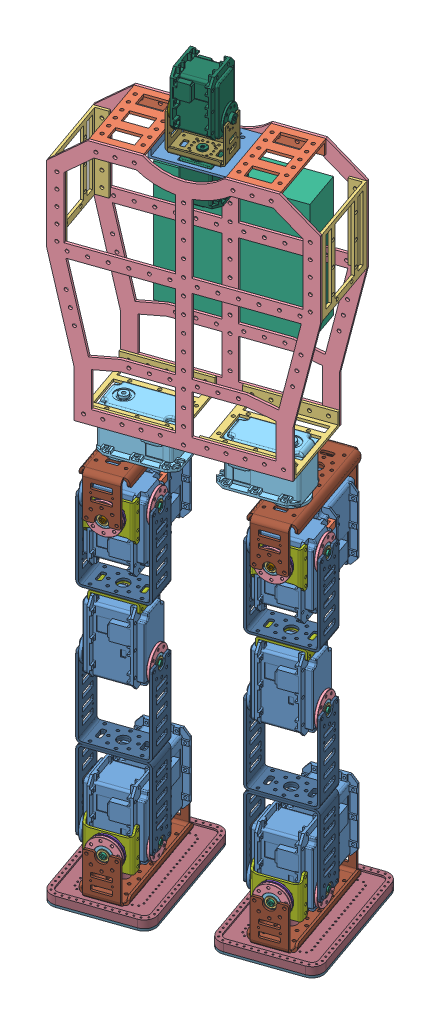
SolidWorks assembly main_new_feet_no_arm_urdf, configuration Default. Lengths in mm.
Overall size (261.31 695.74 185.95).
113 component instances, 25 part files, 43 mates.
Components (placement in the parent):
- leg_l2-1: leg_l2 [Default] at (32.8984 -224.9307 -176.674) x (0.329122 0 0.944287) z (-0.944287 0 0.329122) size (106.88 70.06 58.88)
  - MX-106T_step-1: MX-106T_step [Default] at origin size (40.2 65.92 55.3)
  - MX-106T_step-2: MX-106T_step [Default] at (-44 0 0) x (0 0 1) z (-1 0 0) size (40.2 65.92 55.3)
  - FR08-X101_2017-1: FR08-X101_2017 [Default] at (-27 -7 -17) x (0 -1 0) z (0 0 1) size (28 12.3 4.8)
  - FR08-X101_2017-2: FR08-X101_2017 [Default] at (-27 -7 17) x (0 1 0) z (0 0 -1) size (28 12.3 4.8)
  - RX64-CAP_2017-1: RX64-CAP_2017 [Default] at (0 0 -25.78) x (0.56381 0.825904 0) z (0 0 -1) size (9.5 9.5 2.2)
  - HN05-I101_2017-1: HN05-I101_2017 [Default] at (0 0 -26.02) x (0.824833 -0.565376 0) z (0.565376 0.824833 0) size (28 3.77 28)
  - MF128ZZ_2017-1: MF128ZZ_2017 [Default] at (0 0 -22.3) x (-0.923728 -0.383049 0) z (0.383049 -0.923728 0) size (14 3.48 14)
  - WB_M2.5X8_2017-1: WB_M2.5X8_2017 [Default] at (0 0 -28.08) x (0 0 1) z (0.825904 -0.56381 0) size (5.5 4.5 4.5)
  - FR05-S101_2017-1: FR05-S101_2017 [Default] at (24 0 0) x (0 1 0) z (0 0 1) size (36 9.31 38.02)
  - FR05-F101_2017-1: FR05-F101_2017 [Default] at (24 0 0) x (0 -0.707107 0.707107) z (1 0 0) size (27 27 5)
  - MF128ZZ_2017-2: MF128ZZ_2017 [Default] at (26.3 0 0) x (0 -1 0) z (0 0 1) size (14 3.48 14)
  - WB_M2.5X8_step-1: WB_M2.5X8_step [Default] at (32.08 0 0) x (-1 0 0) z (0 0.546944 0.837169) size (10.5 4.5 4.5)
  - HN05-I101_2017-2: HN05-I101_2017 [Default] at (30.02 0 0) x (0 -1 0) z (0 0 1) size (28 3.77 28)
  - RX64-CAP_2017-2: RX64-CAP_2017 [Default] at (29.78 0 0) x (0 0.837169 -0.546944) z (1 0 0) size (9.5 9.5 2.2)
- leg_l3-2: leg_l3 [Default] at (28.5454 -310.8375 -119.8421) x (0.944287 0 -0.329122) z (0 1 0) size (58.88 41.6 149.21)
  - HW-64106HXL_2017-1: HW-64106HXL_2017 [Default] at (-3.1848 38.233 13.9067) size (56 28 75)
  - FR05-S101_2017-1: FR05-S101_2017 [Default] at (22.8152 52.233 13.9067) x (0 -1 0) z (1 0 0) size (36 9.31 38.02)
  - MX-106T_step-1: MX-106T_step [Default] at (22.8152 52.233 -40.5933) x (0 1 0) z (-1 0 0) size (40.2 65.92 55.3)
  - HN05-I101_2017-1: HN05-I101_2017 [Default] at (48.8352 52.233 -40.5933) x (0 -0.637924 -0.7701) z (0 -0.7701 0.637924) size (28 3.77 28)
  - RX64-CAP_2017-1: RX64-CAP_2017 [Default] at (48.5952 52.233 -40.5933) x (0 0.837169 -0.546944) z (1 0 0) size (9.5 9.5 2.2)
  - MF128ZZ_2017-1: MF128ZZ_2017 [Default] at (45.1152 52.233 -40.5933) x (0 -0.162836 -0.986653) z (0 -0.986653 0.162836) size (14 3.48 14)
  - WB_M2.5X8_2017-1: WB_M2.5X8_2017 [Default] at (50.8952 52.233 -40.5933) x (-1 0 0) z (0 0.546944 0.837169) size (5.5 4.5 4.5)
- leg_l4-1: leg_l4 [Default] at (8.2175 -492.0992 -119.3689) x (0.944287 0 -0.329122) z (0 1 0) size (56 28 150)
  - HW-64106HXL_2017-1: HW-64106HXL_2017 [Default] at (16.1663 31.9894 68.6685) size (56 28 75)
  - HW-64106HXL_2017-2: HW-64106HXL_2017 [Default] at (68.1663 31.9894 68.6685) x (-1 0 0) z (0 0 -1) size (56 28 75)
- leg_l5-1: leg_l5 [Default] at (63.8478 -442.1127 -223.3318) x (0.89528 -0.033567 0.444237) z (-0.424558 -0.366444 0.827931) size (104.02 99.97 119.36)
  - MX-106T_step-1: MX-106T_step [Default] at (-5.1915 -29.4269 71.3073) x (-0.714144 -0.278818 -0.642073) z (-0.699193 0.240141 0.673395) size (40.2 65.92 55.3)
  - MX-106T_step-2: MX-106T_step [Default] at (-36.6138 -41.6949 43.056) x (0.699193 -0.240141 -0.673395) z (-0.714144 -0.278818 -0.642073) size (40.2 65.92 55.3)
  - FR08-X101_2017-1: FR08-X101_2017 [Default] at (-36.5946 -26.3638 62.8539) x (-0.033567 0.929835 -0.366444) z (0.699193 -0.240141 -0.673395) size (28 12.3 4.8)
  - FR08-X101_2017-2: FR08-X101_2017 [Default] at (-12.8221 -34.5286 39.9585) x (0.033567 -0.929835 0.366444) z (-0.699193 0.240141 0.673395) size (28 12.3 4.8)
  - HN05-I101_2017-1: HN05-I101_2017 [Default] at (13.0015 -35.6754 53.7855) x (0.048348 -0.923861 0.379661) z (0.713296 0.298014 0.634347) size (28 3.77 28)
  - RX64-CAP_2017-1: RX64-CAP_2017 [Default] at (12.8337 -35.6178 53.9472) x (-0.430608 0.610431 -0.664793) z (0.699193 -0.240141 -0.673395) size (9.5 9.5 2.2)
  - HN05-I101_2017-2: HN05-I101_2017 [Default] at (16.2471 -21.0568 90.5823) x (0.601193 -0.714144 -0.35856) z (-0.35856 -0.642073 0.677626) size (28 3.77 28)
  - RX64-CAP_2017-2: RX64-CAP_2017 [Default] at (16.0757 -21.1237 90.4282) x (-0.307188 0.949038 -0.070448) z (0.714144 0.278818 0.642073) size (9.5 9.5 2.2)
  - MF128ZZ_2017-1: MF128ZZ_2017 [Default] at (10.4005 -34.7821 56.2906) x (0.048348 -0.923861 0.379661) z (0.713296 0.298014 0.634347) size (14 3.48 14)
  - WB_M2.5X8_2017-1: WB_M2.5X8_2017 [Default] at (14.4419 -36.1701 52.3983) x (-0.699193 0.240141 0.673395) z (0.570706 0.754788 0.323403) size (5.5 4.5 4.5)
  - MF128ZZ_2017-2: MF128ZZ_2017 [Default] at (13.5905 -22.094 88.1938) x (0.601193 -0.714144 -0.35856) z (-0.35856 -0.642073 0.677626) size (14 3.48 14)
  - WB_M2.5X8_2017-2: WB_M2.5X8_2017 [Default] at (17.7183 -20.4824 91.905) x (-0.714144 -0.278818 -0.642073) z (-0.628994 -0.146927 0.763399) size (5.5 4.5 4.5)
  - FR05-S101_2017-1: FR05-S101_2017 [Default] at (11.948 -22.7353 86.717) x (0.033567 -0.929835 0.366444) z (0.699193 -0.240141 -0.673395) size (36 9.31 38.02)
  - FR05-F101_2017-1: FR05-F101_2017 [Default] at (11.948 -22.7353 86.717) x (0.699193 -0.240141 -0.673395) z (0.714144 0.278818 0.642073) size (27 27 5)
- HW-64106HXW_2017-3: HW-64106HXW_2017 [Default] at (141.3019 -187.9307 -286.4689) x (0.329122 0 0.944287) z (0 -1 0) size (105 37.08 40)
- leg_l2-2: leg_l2 [Default] at (148.5736 -224.9307 -216.9914) x (0.329122 0 0.944287) z (-0.944287 0 0.329122) size (106.88 70.06 58.88)
  - MX-106T_step-1: MX-106T_step [Default] at origin size (40.2 65.92 55.3)
  - MX-106T_step-2: MX-106T_step [Default] at (-44 0 0) x (0 0 1) z (-1 0 0) size (40.2 65.92 55.3)
  - FR08-X101_2017-1: FR08-X101_2017 [Default] at (-27 -7 -17) x (0 -1 0) z (0 0 1) size (28 12.3 4.8)
  - FR08-X101_2017-2: FR08-X101_2017 [Default] at (-27 -7 17) x (0 1 0) z (0 0 -1) size (28 12.3 4.8)
  - RX64-CAP_2017-1: RX64-CAP_2017 [Default] at (0 0 -25.78) x (0.56381 0.825904 0) z (0 0 -1) size (9.5 9.5 2.2)
  - HN05-I101_2017-1: HN05-I101_2017 [Default] at (0 0 -26.02) x (0.824833 -0.565376 0) z (0.565376 0.824833 0) size (28 3.77 28)
  - MF128ZZ_2017-1: MF128ZZ_2017 [Default] at (0 0 -22.3) x (-0.923728 -0.383049 0) z (0.383049 -0.923728 0) size (14 3.48 14)
  - WB_M2.5X8_2017-1: WB_M2.5X8_2017 [Default] at (0 0 -28.08) x (0 0 1) z (0.825904 -0.56381 0) size (5.5 4.5 4.5)
  - FR05-S101_2017-1: FR05-S101_2017 [Default] at (24 0 0) x (0 1 0) z (0 0 1) size (36 9.31 38.02)
  - FR05-F101_2017-1: FR05-F101_2017 [Default] at (24 0 0) x (0 -0.707107 0.707107) z (1 0 0) size (27 27 5)
  - MF128ZZ_2017-2: MF128ZZ_2017 [Default] at (26.3 0 0) x (0 -1 0) z (0 0 1) size (14 3.48 14)
  - WB_M2.5X8_step-1: WB_M2.5X8_step [Default] at (32.08 0 0) x (-1 0 0) z (0 0.546944 0.837169) size (10.5 4.5 4.5)
  - HN05-I101_2017-2: HN05-I101_2017 [Default] at (30.02 0 0) x (0 -1 0) z (0 0 1) size (28 3.77 28)
  - RX64-CAP_2017-2: RX64-CAP_2017 [Default] at (29.78 0 0) x (0 0.837169 -0.546944) z (1 0 0) size (9.5 9.5 2.2)
- leg_l3-3: leg_l3 [Default] at (144.2206 -310.8375 -160.1595) x (0.944287 0 -0.329122) z (0 1 0) size (58.88 41.6 149.21)
  - HW-64106HXL_2017-1: HW-64106HXL_2017 [Default] at (-3.1848 38.233 13.9067) size (56 28 75)
  - FR05-S101_2017-1: FR05-S101_2017 [Default] at (22.8152 52.233 13.9067) x (0 -1 0) z (1 0 0) size (36 9.31 38.02)
  - MX-106T_step-1: MX-106T_step [Default] at (22.8152 52.233 -40.5933) x (0 1 0) z (-1 0 0) size (40.2 65.92 55.3)
  - HN05-I101_2017-1: HN05-I101_2017 [Default] at (48.8352 52.233 -40.5933) x (0 -0.637924 -0.7701) z (0 -0.7701 0.637924) size (28 3.77 28)
  - RX64-CAP_2017-1: RX64-CAP_2017 [Default] at (48.5952 52.233 -40.5933) x (0 0.837169 -0.546944) z (1 0 0) size (9.5 9.5 2.2)
  - MF128ZZ_2017-1: MF128ZZ_2017 [Default] at (45.1152 52.233 -40.5933) x (0 -0.162836 -0.986653) z (0 -0.986653 0.162836) size (14 3.48 14)
  - WB_M2.5X8_2017-1: WB_M2.5X8_2017 [Default] at (50.8952 52.233 -40.5933) x (-1 0 0) z (0 0.546944 0.837169) size (5.5 4.5 4.5)
- leg_l4-2: leg_l4 [Default] at (123.8927 -492.0992 -159.6864) x (0.944287 0 -0.329122) z (0 1 0) size (56 28 150)
  - HW-64106HXL_2017-1: HW-64106HXL_2017 [Default] at (16.1663 31.9894 68.6685) size (56 28 75)
  - HW-64106HXL_2017-2: HW-64106HXL_2017 [Default] at (68.1663 31.9894 68.6685) x (-1 0 0) z (0 0 -1) size (56 28 75)
- leg_l5-2: leg_l5 [Default] at (179.523 -442.1127 -263.6493) x (0.89528 -0.033567 0.444237) z (-0.424558 -0.366444 0.827931) size (104.02 99.97 119.36)
  - MX-106T_step-1: MX-106T_step [Default] at (-5.1915 -29.4269 71.3073) x (-0.714144 -0.278818 -0.642073) z (-0.699193 0.240141 0.673395) size (40.2 65.92 55.3)
  - MX-106T_step-2: MX-106T_step [Default] at (-36.6138 -41.6949 43.056) x (0.699193 -0.240141 -0.673395) z (-0.714144 -0.278818 -0.642073) size (40.2 65.92 55.3)
  - FR08-X101_2017-1: FR08-X101_2017 [Default] at (-36.5946 -26.3638 62.8539) x (-0.033567 0.929835 -0.366444) z (0.699193 -0.240141 -0.673395) size (28 12.3 4.8)
  - FR08-X101_2017-2: FR08-X101_2017 [Default] at (-12.8221 -34.5286 39.9585) x (0.033567 -0.929835 0.366444) z (-0.699193 0.240141 0.673395) size (28 12.3 4.8)
  - HN05-I101_2017-1: HN05-I101_2017 [Default] at (13.0015 -35.6754 53.7855) x (0.048348 -0.923861 0.379661) z (0.713296 0.298014 0.634347) size (28 3.77 28)
  - RX64-CAP_2017-1: RX64-CAP_2017 [Default] at (12.8337 -35.6178 53.9472) x (-0.430608 0.610431 -0.664793) z (0.699193 -0.240141 -0.673395) size (9.5 9.5 2.2)
  - HN05-I101_2017-2: HN05-I101_2017 [Default] at (16.2471 -21.0568 90.5823) x (0.601193 -0.714144 -0.35856) z (-0.35856 -0.642073 0.677626) size (28 3.77 28)
  - RX64-CAP_2017-2: RX64-CAP_2017 [Default] at (16.0757 -21.1237 90.4282) x (-0.307188 0.949038 -0.070448) z (0.714144 0.278818 0.642073) size (9.5 9.5 2.2)
  - MF128ZZ_2017-1: MF128ZZ_2017 [Default] at (10.4005 -34.7821 56.2906) x (0.048348 -0.923861 0.379661) z (0.713296 0.298014 0.634347) size (14 3.48 14)
  - WB_M2.5X8_2017-1: WB_M2.5X8_2017 [Default] at (14.4419 -36.1701 52.3983) x (-0.699193 0.240141 0.673395) z (0.570706 0.754788 0.323403) size (5.5 4.5 4.5)
  - MF128ZZ_2017-2: MF128ZZ_2017 [Default] at (13.5905 -22.094 88.1938) x (0.601193 -0.714144 -0.35856) z (-0.35856 -0.642073 0.677626) size (14 3.48 14)
  - WB_M2.5X8_2017-2: WB_M2.5X8_2017 [Default] at (17.7183 -20.4824 91.905) x (-0.714144 -0.278818 -0.642073) z (-0.628994 -0.146927 0.763399) size (5.5 4.5 4.5)
  - FR05-S101_2017-1: FR05-S101_2017 [Default] at (11.948 -22.7353 86.717) x (0.033567 -0.929835 0.366444) z (0.699193 -0.240141 -0.673395) size (36 9.31 38.02)
  - FR05-F101_2017-1: FR05-F101_2017 [Default] at (11.948 -22.7353 86.717) x (0.699193 -0.240141 -0.673395) z (0.714144 0.278818 0.642073) size (27 27 5)
- HW-64106HXW_2017-5: HW-64106HXW_2017 [Default] at (25.6267 -187.9307 -246.1515) x (0.329122 0 0.944287) z (0 -1 0) size (105 37.08 40)
- FR07-H101K-1: FR07-H101K [Default] at (93.0399 76.5333 -190.2227) x (-0.944287 0 0.329122) z (0 1 0) size (44 26 32.5)
- leg_l6_new_feet-1: leg_l6_new_feet [Default] at (87.7926 -593.8701 -169.2992) x (-0.329122 0 -0.944287) z (0 1 0) size (120 80 47.5)
  - HW-64106HXW_2017-1: HW-64106HXW_2017 [Default] at (-3.9692 33.4087 61.4394) size (105 37.08 40)
  - foot_new-1: foot_new [Default] at (44.5308 49.4087 55.9394) x (1 0 0) z (0 -1 0) size (120 7 80)
  - Part4^leg_l6_new_feet-1: Part4^leg_l6_new_feet [Default] at (44.5308 49.4087 55.9394) x (-1 0 0) z (0 0 -1) size (120 80 2) (virtual)
- leg_l6_new_feet-2: leg_l6_new_feet [Default] at (203.4678 -593.8701 -209.6167) x (-0.329122 0 -0.944287) z (0 1 0) size (120 80 47.5)
  - HW-64106HXW_2017-1: HW-64106HXW_2017 [Default] at (-3.9692 33.4087 61.4394) size (105 37.08 40)
  - foot_new-1: foot_new [Default] at (44.5308 49.4087 55.9394) x (1 0 0) z (0 -1 0) size (120 7 80)
  - Part4^leg_l6_new_feet-1: Part4^leg_l6_new_feet [Default] at (44.5308 49.4087 55.9394) x (-1 0 0) z (0 0 -1) size (120 80 2) (virtual)
- head_2_no_camera-1: head_2_no_camera [Default] at (57.4956 210.3096 -243.8587) x (0.944287 0 -0.329122) z (0.329122 0 0.944287) size (44.45 51.16 35.6)
  - MX28_step-1: MX28_step [Default] at (-26.9298 -63.9825 50.4384) x (0 0 1) z (1 0 0) size (35.6 50.71 42.6)
  - MX28_HN07-i101-1: MX28_HN07-i101 [Default] at (-4.5387 -101.2764 62.3462) x (0 0.153917 -0.988084) z (0 0.988084 0.153917) size (22 3.05 22)
  - MF106ZZ-1: MF106ZZ [Défaut] at (-4.3887 -101.2764 62.3462) x (0 0.577041 0.816715) z (0 0.816715 -0.577041) size (11.2 3 11.2)
  - RX28-CAP-1: RX28-CAP [Défaut] at (-4.3887 -101.2764 62.3462) x (0 1 0) z (-1 0 0) size (7.2 7.2 1.8)
- torso_no_arm_motor-1: torso_no_arm_motor [Default] at (90.5715 74.6103 -197.3049) x (0.944287 0 -0.329122) z (0.329122 0 0.944287) size (200 273.5 112.95)
  - torso_frame_head-1: torso_frame_head [Default] at (0 -3.827 -35) size (76 8 58.5)
  - torso_frame_link-1: torso_frame_link [Default] at (-50 -6.241 0) x (0 0 1) z (-1 0 0) size (75.11 12.7 53.47)
  - torso_frame_motor-1: torso_frame_motor [Default] at (-98.857 -88.541 0) x (0 0 1) z (-1 0 0) size (68 70 36.25)
  - torso_main-1: torso_main [Default] at (0 0 34) size (200 228.5 2.29)
  - torso_main-2: torso_main [Default] at (0 0 -36.286) size (200 228.5 2.29)
  - torso_frame_link-2: torso_frame_link [Default] at (50 -6.241 0) x (0 0 1) z (-1 0 0) size (75.11 12.7 53.47)
  - torso_frame_motor-2: torso_frame_motor [Default] at (98.857 -88.541 0) x (0 0 -1) z (1 0 0) size (68 70 36.25)
  - torso_frame_motor-3: torso_frame_motor [Default] at (10 -220.898 0) x (0 0 -1) z (0 -1 0) size (68 70 36.25)
  - torso_frame_motor-4: torso_frame_motor [Default] at (-10 -220.898 0) x (0 0 1) z (0 -1 0) size (68 70 36.25)
  - MX-64T_step-3: MX-64T_step [Default] at (61.25 -239.041 0) x (0 0 -1) z (0 -1 0) size (40.2 62.1 50)
  - MX-64T_step-4: MX-64T_step [Default] at (-61.25 -239.041 0) x (0 0 1) z (0 -1 0) size (40.2 62.1 50)
  - MX28_step-1: MX28_step [Default] at (11.9078 -61.4181 -29.7938) x (-1 0 0) z (0 1 0) size (35.6 50.71 42.6)
  - nuc-1: nuc [Default] at (0 -108.0269 -54.066) size (114.3 111.76 35.56)
- Part1^main_new_feet_no_arm_urdf-1: Part1^main_new_feet_no_arm_urdf [Default] at origin (virtual)
Mates (geometry in assembly coordinates):
- Concentric3: concentric anti-aligned: cylinder of leg_l2-1/HN05-I101_2017-1 through (57.4688 -224.9307 -185.2377) axis (-0.944287 0 0.329122) radius 14; cylinder of leg_l3-2/HW-64106HXL_2017-1 through (59.3385 -224.9307 -185.8894) axis (0.944287 0 -0.329122) radius 5.1
- Concentric4: concentric anti-aligned: cylinder of leg_l3-2/HN05-I101_2017-1 through (57.4688 -351.4307 -185.2377) axis (-0.944287 0 0.329122) radius 14; cylinder of leg_l4-1/HW-64106HXL_2017-1 through (59.3385 -351.4307 -185.8894) axis (0.944287 0 -0.329122) radius 5.1
- Concentric5: concentric anti-aligned: cylinder of leg_l4-1/HW-64106HXL_2017-2 through (6.4584 -495.4307 -167.4586) axis (-0.944287 0 0.329122) radius 5.1; cylinder of leg_l5-1/MX-106T_step-1 through (3.4461 -495.4307 -166.4087) axis (0.944287 0 -0.329122) radius 5
- Coincident5: coincident anti-aligned: plane of leg_l4-1/HW-64106HXL_2017-2 through (8.347 -495.4307 -168.1168) normal (0.944287 0 -0.329122); plane of leg_l5-1/MX-106T_step-1 through (8.347 -495.4307 -168.1168) normal (-0.944287 0 0.329122)
- Coincident6: coincident anti-aligned: plane of leg_l2-1/MX-106T_step-1 through (8.347 -224.9307 -168.1168) normal (-0.944287 0 0.329122); plane of leg_l3-2/HW-64106HXL_2017-1 through (8.347 -224.9307 -168.1168) normal (0.944287 0 -0.329122)
- Coincident7: coincident anti-aligned: plane of leg_l2-1/MX-106T_step-1 through (8.347 -224.9307 -168.1168) normal (-0.944287 0 0.329122); plane of leg_l3-2/HW-64106HXL_2017-1 through (8.347 -224.9307 -168.1168) normal (0.944287 0 -0.329122)
- Coincident8: coincident anti-aligned: plane of leg_l3-2/MX-106T_step-1 through (8.347 -351.4307 -168.1168) normal (-0.944287 0 0.329122); plane of leg_l4-1/HW-64106HXL_2017-1 through (8.347 -351.4307 -168.1168) normal (0.944287 0 -0.329122)
- Concentric8: concentric aligned: cylinder of HW-64106HXW_2017-3 through (159.4347 -224.9307 -185.83) axis (0.329122 0 0.944287) radius 5.1; cylinder of leg_l2-2/MX-106T_step-2 through (123.8269 -224.9307 -287.9924) axis (0.329122 0 0.944287) radius 5
- Coincident11: coincident anti-aligned: plane of HW-64106HXW_2017-3 through (125.5351 -210.0147 -283.0916) normal (0.329122 0 0.944287); plane of leg_l2-2/MX-106T_step-2 through (125.5351 -224.9307 -283.0916) normal (-0.329122 0 -0.944287)
- Concentric9: concentric aligned: cylinder of leg_l2-2/MX-106T_step-1 through (119.1213 -224.9307 -206.7261) axis (0.944287 0 -0.329122) radius 5; cylinder of leg_l3-3/HW-64106HXL_2017-1 through (124.0222 -224.9307 -208.4343) axis (0.944287 0 -0.329122) radius 5.1
- Coincident12: coincident anti-aligned: plane of leg_l2-2/MX-106T_step-1 through (124.0222 -224.9307 -208.4343) normal (-0.944287 0 0.329122); plane of leg_l3-3/HW-64106HXL_2017-1 through (124.0222 -224.9307 -208.4343) normal (0.944287 0 -0.329122)
- Concentric10: concentric aligned: cylinder of leg_l3-3/MX-106T_step-1 through (119.1213 -351.4307 -206.7261) axis (0.944287 0 -0.329122) radius 5; cylinder of leg_l4-2/HW-64106HXL_2017-1 through (124.0222 -351.4307 -208.4343) axis (0.944287 0 -0.329122) radius 5.1
- Coincident13: coincident anti-aligned: plane of leg_l3-3/MX-106T_step-1 through (124.0222 -351.4307 -208.4343) normal (-0.944287 0 0.329122); plane of leg_l4-2/HW-64106HXL_2017-1 through (124.0222 -351.4307 -208.4343) normal (0.944287 0 -0.329122)
- Concentric13: concentric anti-aligned: cylinder of leg_l4-2/HW-64106HXL_2017-2 through (122.1336 -495.4307 -207.776) axis (-0.944287 0 0.329122) radius 5.1; cylinder of leg_l5-2/MX-106T_step-1 through (119.1213 -495.4307 -206.7261) axis (0.944287 0 -0.329122) radius 5
- Coincident16: coincident anti-aligned: plane of leg_l4-2/HW-64106HXL_2017-2 through (124.0222 -495.4307 -208.4343) normal (0.944287 0 -0.329122); plane of leg_l5-2/MX-106T_step-1 through (124.0222 -495.4307 -208.4343) normal (-0.944287 0 0.329122)
- Parallel3: parallel anti-aligned: plane of leg_l2-1/MX-106T_step-1 through (32.8984 -224.9307 -176.674) normal (0.329122 0 0.944287); plane of leg_l3-2/HW-64106HXL_2017-1 through (12.9547 -296.9307 -154.8968) normal (-0.329122 0 -0.944287)
- Parallel4: parallel aligned: plane of leg_l3-2/MX-106T_step-1 through (32.8984 -351.4307 -176.674) normal (-0.329122 0 -0.944287); plane of leg_l4-1/HW-64106HXL_2017-1 through (12.9547 -423.4307 -154.8968) normal (-0.329122 0 -0.944287)
- Parallel5: parallel aligned: plane of leg_l4-1/HW-64106HXL_2017-2 through (62.0576 -423.4307 -172.0111) normal (-0.329122 0 -0.944287); plane of leg_l5-1/MX-106T_step-1 through (32.8984 -495.4307 -176.674) normal (-0.329122 0 -0.944287)
- Parallel8: parallel aligned: plane of HW-64106HXW_2017-3 through (141.3019 -187.9307 -286.4689) normal (-0.944287 0 0.329122); plane of leg_l2-2/MX-106T_step-1 through (148.5736 -224.9307 -216.9914) normal (-0.944287 0 0.329122)
- Parallel9: parallel anti-aligned: plane of leg_l2-2/MX-106T_step-1 through (148.5736 -224.9307 -216.9914) normal (0.329122 0 0.944287); plane of leg_l3-3/HW-64106HXL_2017-1 through (128.6299 -296.9307 -195.2142) normal (-0.329122 0 -0.944287)
- Parallel10: parallel aligned: plane of leg_l3-3/MX-106T_step-1 through (148.5736 -351.4307 -216.9914) normal (-0.329122 0 -0.944287); plane of leg_l4-2/HW-64106HXL_2017-1 through (128.6299 -423.4307 -195.2142) normal (-0.329122 0 -0.944287)
- Parallel11: parallel aligned: plane of leg_l4-2/HW-64106HXL_2017-2 through (177.7328 -423.4307 -212.3286) normal (-0.329122 0 -0.944287); plane of leg_l5-2/MX-106T_step-1 through (148.5736 -495.4307 -216.9914) normal (-0.329122 0 -0.944287)
- Concentric19: concentric aligned: cylinder of leg_l2-1/MX-106T_step-2 through (8.1517 -224.9307 -247.6749) axis (0.329122 0 0.944287) radius 5; cylinder of HW-64106HXW_2017-5 through (43.7595 -224.9307 -145.5125) axis (0.329122 0 0.944287) radius 5.1
- Coincident39: coincident anti-aligned: plane of leg_l2-1/MX-106T_step-2 through (9.8599 -224.9307 -242.7741) normal (-0.329122 0 -0.944287); plane of HW-64106HXW_2017-5 through (9.8599 -210.0147 -242.7741) normal (0.329122 0 0.944287)
- Parallel18: parallel aligned: plane of leg_l2-1/MX-106T_step-1 through (32.8984 -224.9307 -176.674) normal (-0.944287 0 0.329122); plane of HW-64106HXW_2017-5 through (25.6267 -187.9307 -246.1515) normal (-0.944287 0 0.329122)
- Concentric34: concentric anti-aligned: cylinder of FR07-H101K-1 through (72.2656 109.0333 -182.982) axis (0.944287 0 -0.329122) radius 4; cylinder of head_2_no_camera-1/MX28_step-1 through (115.3652 109.0333 -198.004) axis (-0.944287 0 0.329122) radius 11
- Concentric35: concentric aligned: cylinder of FR07-H101K-1 through (93.0399 78.0333 -190.2227) axis (0 -1 0) radius 4; cylinder of torso_no_arm_motor-1/MX28_step-1 through (93.0399 79.6758 -190.2227) axis (0 -1 0) radius 4
- Coincident59: coincident anti-aligned: plane of FR07-H101K-1 through (93.0399 76.5333 -190.2227) normal (0 -1 0); plane of torso_no_arm_motor-1/MX28_step-1 through (93.0399 76.5333 -190.2227) normal (0 1 0)
- Concentric36: concentric anti-aligned: cylinder of HW-64106HXW_2017-5 through (32.7339 -306.252 -177.1461) axis (0 -1 0) radius 5.1; cylinder of torso_no_arm_motor-1/MX-64T_step-4 through (32.7339 -192.8057 -177.1461) axis (0 1 0) radius 14
- Coincident61: coincident anti-aligned: plane of HW-64106HXW_2017-5 through (34.7909 -187.9307 -171.2443) normal (0 1 0); plane of torso_no_arm_motor-1/MX-64T_step-4 through (32.7339 -187.9307 -177.1461) normal (0 -1 0)
- Parallel32: parallel aligned: plane of HW-64106HXW_2017-5 through (8.9735 -191.5147 -188.9857) normal (-0.944287 0 0.329122); plane of torso_no_arm_motor-1/MX-64T_step-4 through (25.2304 -143.9307 -159.1754) normal (-0.944287 0 0.329122)
- Concentric37: concentric anti-aligned: cylinder of HW-64106HXW_2017-3 through (148.4091 -306.252 -217.4636) axis (0 -1 0) radius 5.1; cylinder of torso_no_arm_motor-1/MX-64T_step-3 through (148.4091 -192.8057 -217.4636) axis (0 1 0) radius 14
- Coincident63: coincident anti-aligned: plane of HW-64106HXW_2017-3 through (150.4661 -187.9307 -211.5618) normal (0 1 0); plane of torso_no_arm_motor-1/MX-64T_step-3 through (148.4091 -187.9307 -217.4636) normal (0 -1 0)
- Parallel33: parallel aligned: plane of HW-64106HXW_2017-3 through (159.6628 -191.5147 -241.507) normal (0.944287 0 -0.329122); plane of torso_no_arm_motor-1/MX-64T_step-3 through (155.9125 -143.9307 -235.4343) normal (0.944287 0 -0.329122)
- Concentric38: concentric anti-aligned: cylinder of leg_l5-1/HN05-I101_2017-2 through (42.7787 -495.4307 -148.3265) axis (-0.329122 0 -0.944287) radius 14; circle of leg_l6_new_feet-1/HW-64106HXW_2017-1
- Parallel34: parallel aligned: plane of leg_l5-1/MX-106T_step-1 through (49.8448 -509.9307 -197.936) normal (0 -1 0); plane of leg_l6_new_feet-1/foot_new-1 through (26.4806 -537.9307 -195.0876) normal (0 -1 0)
- Concentric39: concentric aligned: cylinder of leg_l5-2/HN05-I101_2017-2 through (158.4539 -495.4307 -188.6439) axis (-0.329122 0 -0.944287) radius 14; cylinder of leg_l6_new_feet-2/HW-64106HXW_2017-1 through (124.8768 -495.4307 -284.9801) axis (-0.329122 0 -0.944287) radius 5.1
- Parallel35: parallel aligned: plane of leg_l5-2/MX-106T_step-1 through (165.52 -509.9307 -238.2534) normal (0 -1 0); plane of leg_l6_new_feet-2/foot_new-1 through (142.1558 -537.9307 -235.405) normal (0 -1 0)
- Coincident70: coincident anti-aligned: plane of leg_l5-1/MX-106T_step-2 through (9.8599 -495.4307 -242.7741) normal (-0.329122 0 -0.944287); plane of leg_l6_new_feet-1/HW-64106HXW_2017-1 through (9.8599 -510.3468 -242.7741) normal (0.329122 0 0.944287)
- Coincident71: coincident anti-aligned: plane of leg_l5-2/MX-106T_step-2 through (125.5351 -495.4307 -283.0916) normal (-0.329122 0 -0.944287); plane of leg_l6_new_feet-2/HW-64106HXW_2017-1 through (125.5351 -510.3468 -283.0916) normal (0.329122 0 0.944287)
- Coincident72: coincident anti-aligned: plane of FR07-H101K-1 through (112.3978 109.0333 -196.9697) normal (-0.944287 0 0.329122); plane of head_2_no_camera-1/MX28_step-1 through (112.3978 109.0333 -196.9697) normal (0.944287 0 -0.329122)
- Parallel36: parallel aligned: plane of head_2_no_camera-1/MX28_step-1 through (86.3865 141.6333 -169.0535) normal (0.329122 0 0.944287); plane of FR07-H101K-1 through (77.3023 76.5333 -173.0885) normal (0.329122 0 0.944287)
- Parallel37: parallel aligned: plane of FR07-H101K-1 through (77.3023 76.5333 -173.0885) normal (0.329122 0 0.944287); plane of torso_no_arm_motor-1/torso_main-1 through (102.514 114.6103 -163.0404) normal (0.329122 0 0.944287)
